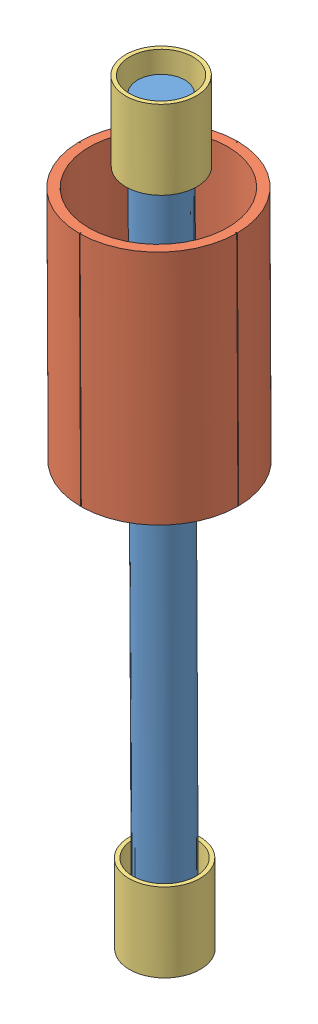
SolidWorks assembly FinalFinal11, configuration Default. Lengths in mm.
Overall size (30.66 72.45 49.76).
4 component instances, 5 part files, 2 mates.
Components (placement in the parent):
- RodCapacitance-1: RodCapacitance [Default] at (-34.9973 26.4173 110.2163) x (-0.024859 -0.005123 0.999678) z (-0.999691 0.000127 -0.024859) size (3 45 3)
- PZTFINAL-1: PZTFINAL [Default] at (-34.9374 51.4338 110.6053) x (1 0 0) z (0 -0.005125 0.999987) size (10 15 10)
- Ring-1: Ring [Default] at (-34.9973 72.4349 110.4522) x (0 -0.999987 -0.005125) z (0.005125 -0.005125 0.999974) size (5 4.5 4.5)
- Ring-2: Ring [Default] at (-34.9973 29.4354 110.2318) x (0 -0.999987 -0.005125) z (0.684903 0.003734 -0.728625) size (5 4.5 4.5)
Mates (geometry in assembly coordinates):
- Concentric18: concentric anti-aligned: circle of RodCapacitance-1; circle of Ring-1
- Concentric19: concentric anti-aligned: circle of RodCapacitance-1; circle of Ring-2
